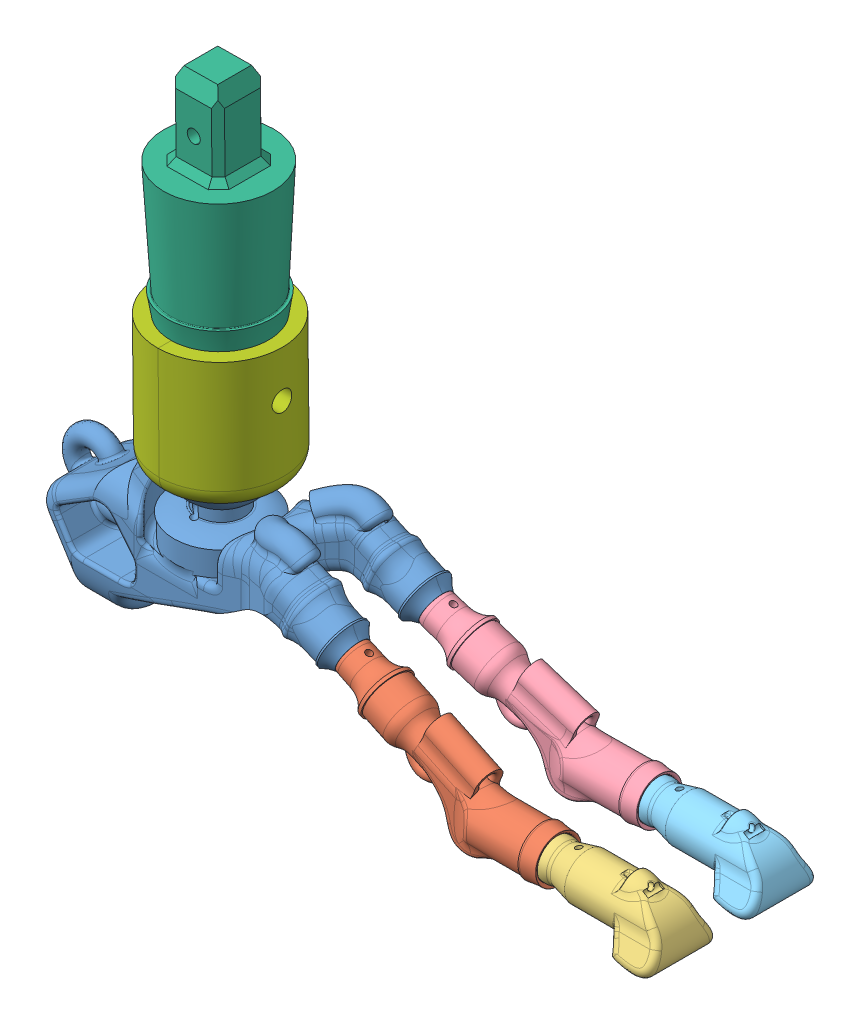
SolidWorks assembly Foot, configuration Default. Lengths in mm.
Overall size (260.5 204.47 79.33).
8 component instances, 7 part files, 12 mates.
Components (placement in the parent):
- Talus - New-1: Talus - New [Default] at origin size (131.32 86.19 51)
- Metatarsals-1: Metatarsals [Default] at (104.0952 -44.3034 18.1531) x (-0.929116 0.366544 -0.048875) z (0.042994 -0.024198 -0.998782) size (95.04 30.95 38.02)
- Phalanges-1: Phalanges [Default] at (172.2396 -55.1541 19.5999) size (57.16 24.44 28.69)
- Metatarsals - Left side-1: Metatarsals - Left side [Default] at (104.1326 -44.2161 -17.9587) x (-0.930097 0.364252 0.047332) z (-0.050841 -0.000045 -0.998707) size (95.04 30.95 38.02)
- Phalanges - Left side-1: Phalanges - Left side [Default] at (172.3053 -54.9301 -19.5095) size (57.16 24.44 28.69)
- Tibial End-1: Tibial End [Default] at (0.0768 -6.9967 0) x (0 0 1) z (-0.99994 -0.010975 0) size (42.45 113.08 48.21)
- Sleeve-4: Sleeve [Default] at (0.0784 -7.1467 0) x (-0.99994 -0.010975 0) z (0 0 -1) size (26.67 50.8 48.26)
- Sleeve-5: Sleeve [Default] at (0.0784 -7.1467 0) x (0.99994 0.010975 0) z (0 0 1) size (26.67 50.8 48.26)
Mates (geometry in assembly coordinates):
- Concentric1: concentric: sphere of Metatarsals-1; sphere of Talus - New-1
- Concentric2: concentric: sphere of Phalanges-1; sphere of Metatarsals-1
- Concentric3: concentric: sphere of Talus - New-1; sphere of Metatarsals - Left side-1
- Concentric4: concentric: sphere of Phalanges - Left side-1; sphere of Metatarsals - Left side-1
- Coincident2: coincident: cone of Tibial End-1 through (0.0768 -6.9967 0) axis (0.010975 -0.99994 0); cone of Sleeve-5 through (0.0768 -6.9967 0) axis (0.010975 -0.99994 0)
- Coincident9: coincident: cone of Tibial End-1 through (0.0768 -6.9967 0) axis (0.010975 -0.99994 0); cone of Sleeve-4 through (0.0768 -6.9967 0) axis (0.010975 -0.99994 0)
- Coincident10: coincident: plane of Sleeve-4 through (0.0784 -7.1467 0) normal (0.99994 0.010975 0); plane of Sleeve-5 through (0.0784 -7.1467 0) normal (-0.99994 -0.010975 0)
- Coincident12: coincident: sphere of Talus - New-1; circle of Tibial End-1
- Parallel2: parallel: cone of Tibial End-1 through (0.0768 -6.9967 0) axis (0.010975 -0.99994 0); cylinder of Sleeve-5 through (-0.4791 43.6502 0) axis (0.010975 -0.99994 0) radius 24.13
- Parallel4: parallel: plane of Talus - New-1 through (0 0 17.78) normal (0 0 1); plane of Tibial End-1 through (-10.9112 126.2408 9.525) normal (0 0 1)
- LimitAngle3: limit planar angle = 1.581772 rad: plane of Tibial End-1 through (8.1376 126.4499 9.525) normal (0.99994 0.010975 0); plane of assembly through (0 0 0) normal (0 1 0)
- Concentric5: concentric: cylinder of Tibial End-1 through (20.9155 26.0009 0) axis (-0.99994 -0.010975 0) radius 3.81; cylinder of Sleeve-5 through (38.3228 26.192 0) axis (-0.99994 -0.010975 0) radius 3.81
